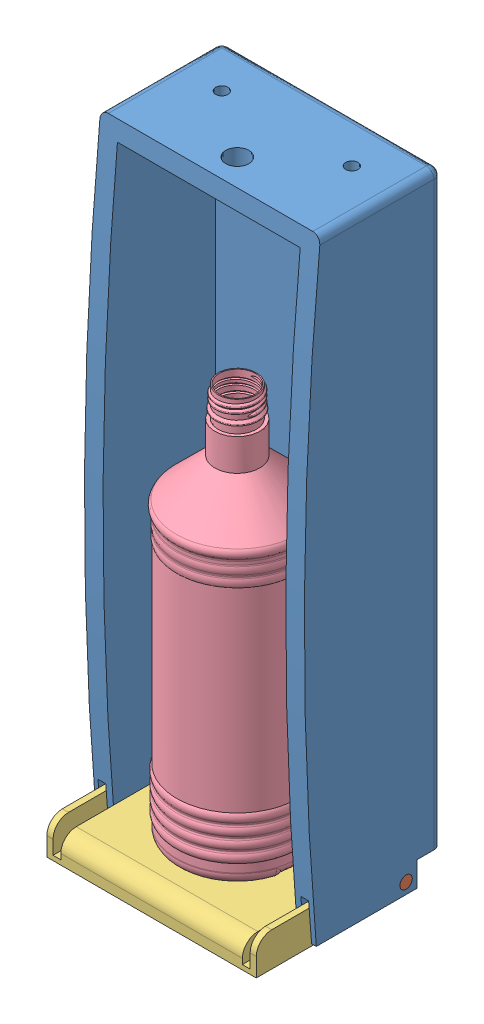
SolidWorks assembly chamber_product2, configuration Default. Lengths in mm.
Overall size (150 398 116).
4 component instances, 4 part files, 6 mates.
Components (placement in the parent):
- base_product2-1: base_product2 [Default] at (164.5564 96.0696 403.5318) x (-1 0 0) z (0 0 -1) size (142 396 88.73)
- arbre servo-1: arbre servo [Default] at (85.5564 113.0696 365.5318) x (0 0 -1) z (1 0 0) size (8 8 150)
- bottle base_product 2-2: bottle base_product 2 [Default] at (164.1814 126.0696 408.5318) x (-1 0 0) z (0 0 1) size (135.25 22 100)
- Battery Water Bottle HDPE-2: Battery Water Bottle HDPE [Default] at (164.5564 122.7501 403.5318) x (-0.998313 0 -0.058067) z (0.058067 0 -0.998313) size (81.4 253.7 81.4)
Mates (geometry in assembly coordinates):
- Coincident1: coincident aligned: plane of trial-1 through (235.5564 106.0696 448.5318) normal (1 0 0); circle of servo-1
- Concentric1: concentric anti-aligned: circle of trial-1; circle of servo-1
- Concentric3: concentric aligned: circle of servo-1; circle of bottle base-2
- LimitAngle1: limit planar angle = 0 rad anti-aligned: plane of trial-1 through (164.5564 106.0696 403.5318) normal (0 -1 0); plane of bottle base-2 through (100.5564 107.0696 358.5318) normal (0 1 0)
- LimitDistance1: limit distance = 0 mm: plane of trial-1 through (96.5564 131.0696 356.774) normal (1 0 0); line of bottle base-2 through (96.5564 126.0696 448.5318) axis (0 0 -1)
- Concentric5: concentric anti-aligned: circle of trial-1; circle of Battery Water Bottle HDPE-2
